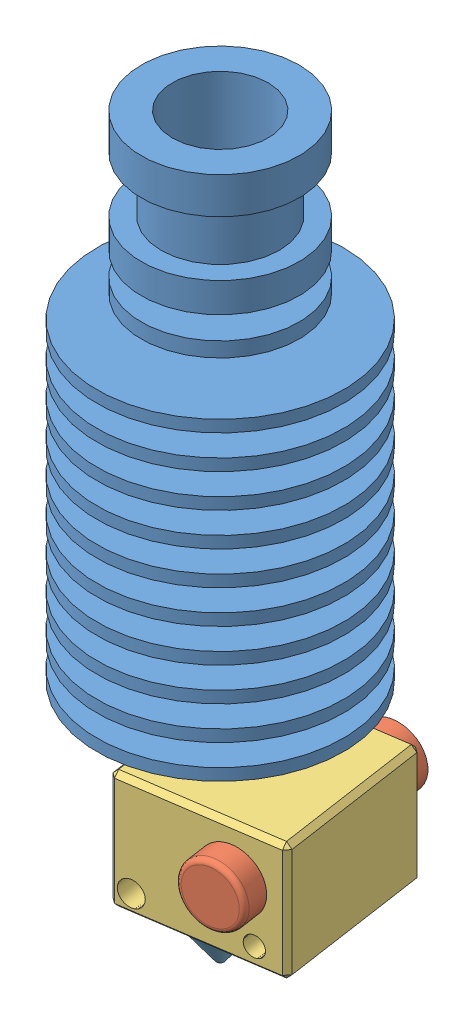
SolidWorks assembly hot end, configuration Varsayılan. Lengths in mm.
Overall size (25.54 74.6 34.92).
6 component instances, 6 part files, 8 mates.
Components (placement in the parent):
- E3D Heatsink-1: E3D Heatsink [1.75 Bowden] at (-13.2854 1.8762 50.1) size (25 50.1 25)
- cartridge heater-1: cartridge heater [Default] at (-6.4156 -33.1738 48.7024) x (0.145498 0 0.989359) z (-0.989359 0 0.145498) size (32 6.2 6.2)
- E3D Heat Block-1: E3D Heat Block [Default] at (-9.3279 -40.1738 49.518) x (0.989359 0 -0.145498) z (0.145498 0 0.989359) size (16 12 16)
- Heatbreak 30mm-1: Heatbreak 30mm [Varsayılan] at (-11.9317 -4.6738 25.7324) x (0.404309 0 -0.914622) z (0 -1 0) size (6 6 30)
- nozzle-1: nozzle [Varsayılan] at (-6.8546 -40.1738 49.4378) x (1 0 0) z (0 -1 0) size (7.04 6.27 13)
- thermistor-1: thermistor [Default] at (-5.4488 -38.1738 41.5306) x (0.957403 -0.252103 -0.140798) z (-0.24942 -0.967701 0.03668) size (2 13.25 2)
Mates (geometry in assembly coordinates):
- Eş Merkezli1: concentric anti-aligned: cylinder of E3D Heatsink-1 through (-13.2854 -23.1738 50.1) axis (0 -1 0) radius 3; cylinder of Heatbreak 30mm-1 through (-13.2854 -34.6738 50.1) axis (0 1 0) radius 3
- Çakışık1: coincident aligned: circle of E3D Heatsink-1; circle of Heatbreak 30mm-1
- Eş Merkezli3: concentric aligned: cylinder of E3D Heat Block-1 through (-13.2854 -28.1738 50.1) axis (0 1 0) radius 2.5; cylinder of nozzle-1 through (-13.2854 -32.2642 50.1) axis (0 1 0) radius 2.634
- Çakışık2: coincident anti-aligned: plane of E3D Heat Block-1 through (-9.3279 -40.1738 49.518) normal (0 -1 0); plane of nozzle-1 through (-6.8546 -40.1738 49.4378) normal (0 1 0)
- Kilitle1: lock: unknown of cartridge heater-1; unknown of E3D Heat Block-1
- Eş Merkezli5: concentric aligned: cylinder of E3D Heat Block-1 through (-13.2854 -28.1738 50.1) axis (0 1 0) radius 2.5; cylinder of Heatbreak 30mm-1 through (-13.2854 -34.6738 50.1) axis (0 1 0) radius 3
- Çakışık4: coincident anti-aligned: plane of Heatbreak 30mm-1 through (-13.2854 -34.6738 50.1) normal (0 -1 0); plane of nozzle-1 through (-13.3524 -34.6738 50.216) normal (0 1 0)
- Kilitle2: lock: unknown of E3D Heat Block-1; unknown of thermistor-1
